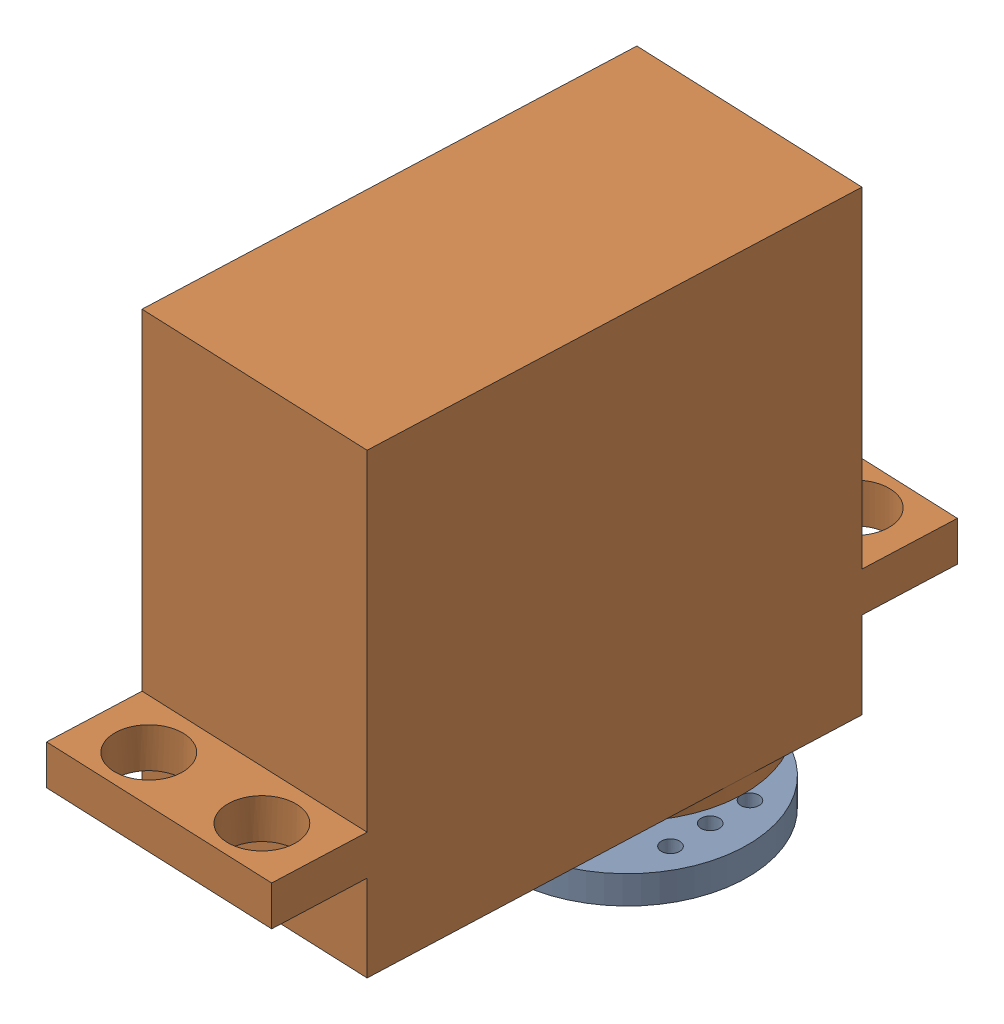
SolidWorks assembly servo_plus_horn, configuration 默认. Lengths in mm.
Overall size (22.4 46.4 57.18).
2 component instances, 2 part files, 2 mates.
Components (placement in the parent):
- horn_only-1: horn_only [默认] at (0.8167 -3.4508 0) size (20.6 5.5 20.6)
- servo_only-1: servo_only [默认] at (0.394 3.8492 10.2913) x (0.999158 0 0.041039) z (0 -1 0) size (20.1 56.4 44.2)
Mates (geometry in assembly coordinates):
- 同心1: concentric anti-aligned: circle of horn_only-1; circle of servo_only-1
- 距离2: distance = 0.6 mm anti-aligned: plane of horn_only-1 through (0.8167 2.0492 0) normal (0 1 0); plane of servo_only-1 through (0.394 2.6492 10.2913) normal (0 -1 0)
